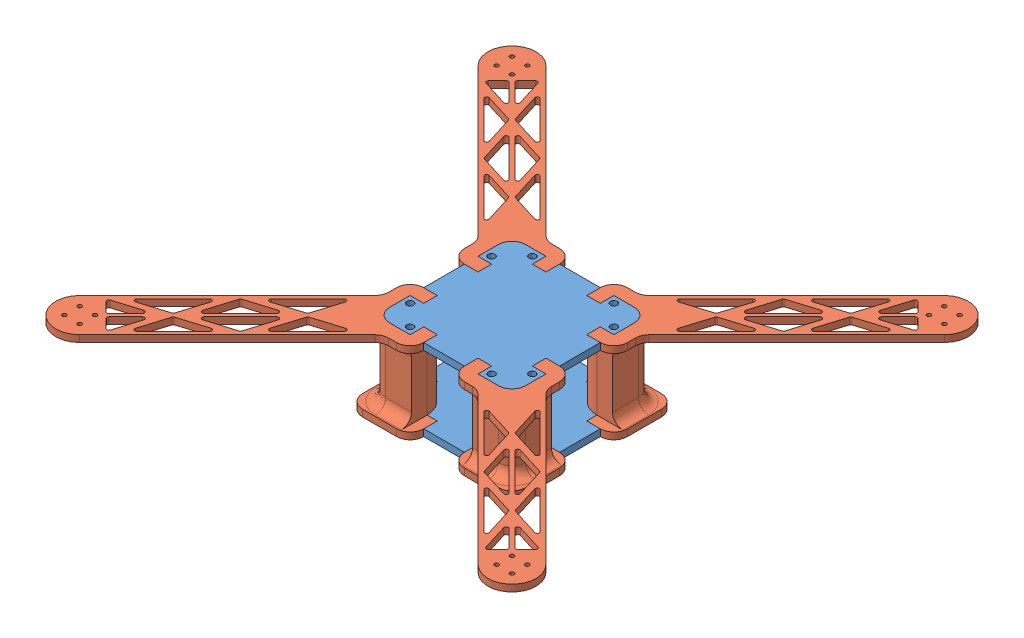
SolidWorks assembly DroneAssembly, configuration Default. Lengths in mm.
Overall size (382.36 60 382.36).
6 component instances, 2 part files, 15 mates.
Components (placement in the parent):
- ElectronicsPlates-1: ElectronicsPlates [Default] at (35.9216 43.5711 81.6544) size (100 5 100)
- Arm-1: Arm [Default] at (85.9216 98.5711 131.6544) x (0.707107 0 0.707107) z (-0.707107 0 0.707107) size (203.8 60 55.36)
- Arm-2: Arm [Default] at (-14.0784 98.5711 131.6544) x (-0.707107 0 0.707107) z (-0.707107 0 -0.707107) size (203.8 60 55.36)
- Arm-3: Arm [Default] at (85.9216 98.5711 31.6544) x (0.707107 0 -0.707107) z (0.707107 0 0.707107) size (203.8 60 55.36)
- Arm-4: Arm [Default] at (-14.0784 98.5711 31.6544) x (-0.707107 0 -0.707107) z (0.707107 0 -0.707107) size (203.8 60 55.36)
- ElectronicsPlates-2: ElectronicsPlates [Default] at (35.9216 98.5711 81.6544) size (100 5 100)
Mates (geometry in assembly coordinates):
- Coincident1: coincident anti-aligned: plane of ElectronicsPlates-1 through (35.9216 48.5711 81.6544) normal (0 1 0); plane of Arm-1 through (85.9216 48.5711 131.6544) normal (0 -1 0)
- Coincident2: coincident anti-aligned: plane of ElectronicsPlates-1 through (85.9216 48.5711 81.6544) normal (1 0 0); plane of Arm-1 through (85.9216 43.5711 121.6544) normal (-1 0 0)
- Coincident3: coincident anti-aligned: plane of ElectronicsPlates-1 through (35.9216 48.5711 131.6544) normal (0 0 1); plane of Arm-1 through (75.9216 43.5711 131.6544) normal (0 0 -1)
- Coincident4: coincident anti-aligned: plane of ElectronicsPlates-1 through (35.9216 48.5711 81.6544) normal (0 1 0); plane of Arm-4 through (-14.0784 48.5711 31.6544) normal (0 -1 0)
- Coincident5: coincident anti-aligned: plane of ElectronicsPlates-1 through (-14.0784 48.5711 81.6544) normal (-1 0 0); plane of Arm-4 through (-14.0784 43.5711 41.6544) normal (1 0 0)
- Coincident6: coincident anti-aligned: plane of ElectronicsPlates-1 through (35.9216 48.5711 31.6544) normal (0 0 -1); plane of Arm-4 through (-4.0784 43.5711 31.6544) normal (0 0 1)
- Coincident7: coincident anti-aligned: plane of ElectronicsPlates-1 through (35.9216 48.5711 81.6544) normal (0 1 0); plane of Arm-2 through (-14.0784 48.5711 131.6544) normal (0 -1 0)
- Coincident8: coincident anti-aligned: plane of ElectronicsPlates-1 through (-14.0784 48.5711 81.6544) normal (-1 0 0); plane of Arm-2 through (-14.0784 43.5711 121.6544) normal (1 0 0)
- Coincident9: coincident anti-aligned: plane of ElectronicsPlates-1 through (35.9216 48.5711 131.6544) normal (0 0 1); plane of Arm-2 through (-4.0784 43.5711 131.6544) normal (0 0 -1)
- Coincident10: coincident anti-aligned: plane of ElectronicsPlates-1 through (35.9216 48.5711 81.6544) normal (0 1 0); plane of Arm-3 through (85.9216 48.5711 31.6544) normal (0 -1 0)
- Coincident11: coincident anti-aligned: plane of ElectronicsPlates-1 through (35.9216 48.5711 31.6544) normal (0 0 -1); plane of Arm-3 through (75.9216 43.5711 31.6544) normal (0 0 1)
- Coincident12: coincident anti-aligned: plane of ElectronicsPlates-1 through (85.9216 48.5711 81.6544) normal (1 0 0); plane of Arm-3 through (85.9216 43.5711 41.6544) normal (-1 0 0)
- Coincident13: coincident anti-aligned: plane of Arm-2 through (-14.0784 98.5711 131.6544) normal (0 1 0); plane of ElectronicsPlates-2 through (35.9216 98.5711 81.6544) normal (0 -1 0)
- Concentric1: concentric aligned: cylinder of Arm-3 through (75.9216 103.5711 41.6544) axis (0 -1 0) radius 10; cylinder of ElectronicsPlates-2 through (75.9216 103.5711 41.6544) axis (0 -1 0) radius 10
- Concentric2: concentric aligned: cylinder of Arm-2 through (-4.0784 103.5711 121.6544) axis (0 -1 0) radius 10; cylinder of ElectronicsPlates-2 through (-4.0784 103.5711 121.6544) axis (0 -1 0) radius 10
